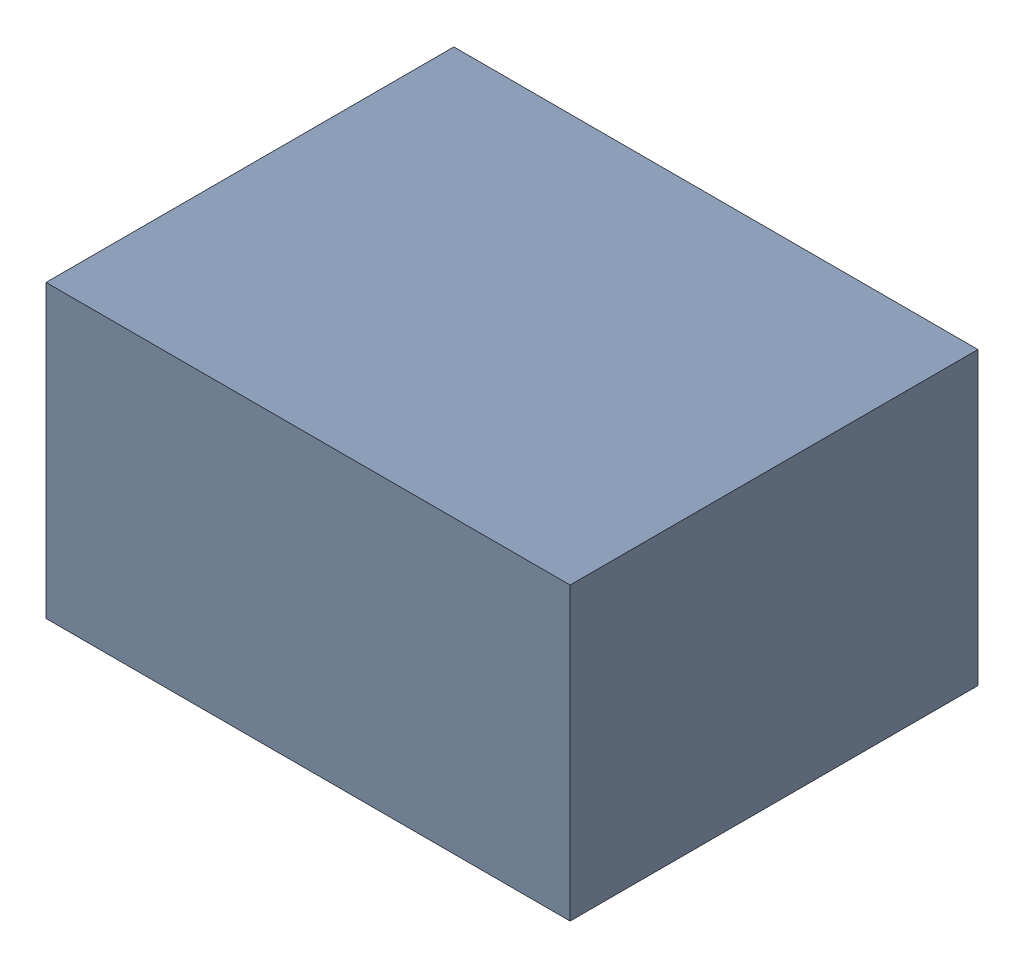
SolidWorks assembly C40, configuration Default. Lengths in mm.
Overall size (1.8 1 1.4).
3 component instances, 2 part files, 0 mates.
Components (placement in the parent):
- 1088884976-1: 1088884976 [Default] at (10.525 22.55 -3.044) size (1.8 1 1.4)
  - Extruded-47-1: Extruded-47 [Default] at origin size (1.8 1 1.4)
- C0603-1: C0603 [Default] at (9.725 22.9501 -1.644) x (1 0 0) z (0 1 0) size (1.6 0.5 0.8)
